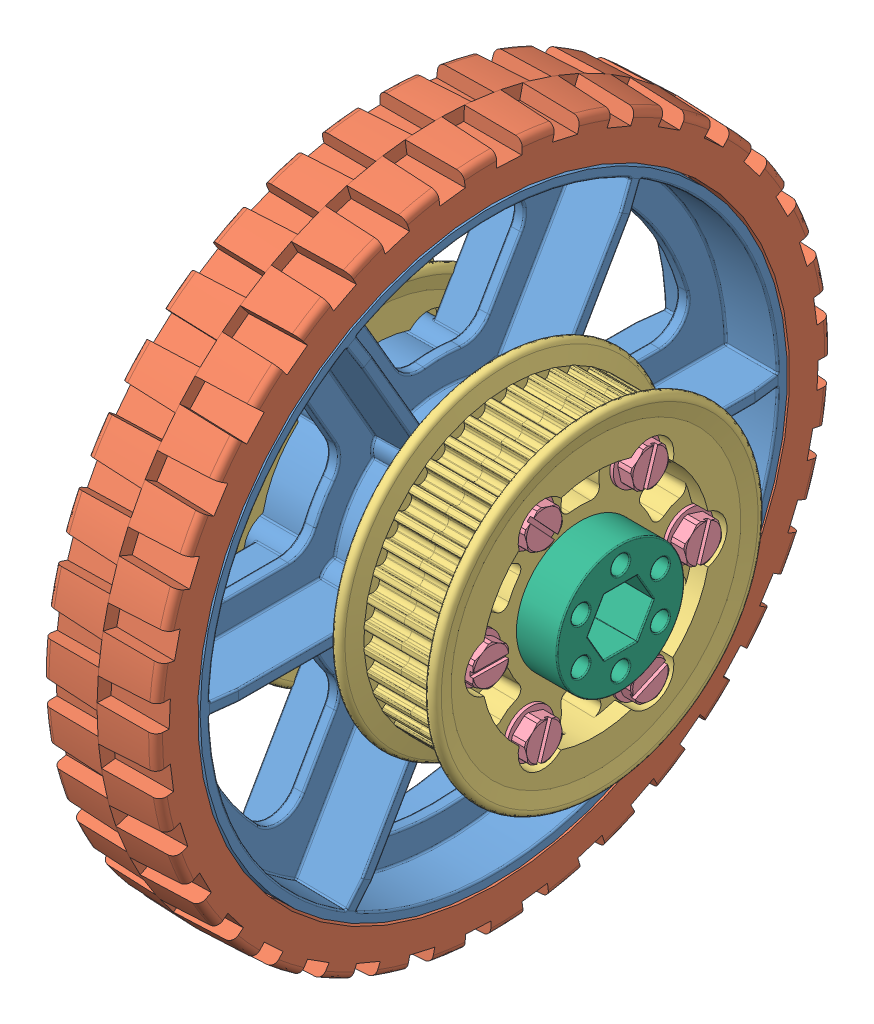
SolidWorks assembly Wheel_6inHiGrip_Center, configuration Default. Lengths in mm.
Overall size (81.42 191.55 191.55).
21 component instances, 6 part files, 0 mates.
Components (placement in the parent):
- Wheel_6inHiGrip-1: Wheel_6inHiGrip [Default] at (83.7987 67.439 110.9939) size (34.93 191.55 191.55)
  - Wheel_6inHiGrip_Wheel-1: Wheel_6inHiGrip_Wheel [Default] at (-52.6446 9.4231 21.378) size (34.93 132.08 132.08)
  - Wheel_6inHiGrip_Tread-1: Wheel_6inHiGrip_Tread [Default] at (-65.3446 9.4231 21.378) x (0 -0.304368 -0.952555) z (1 0 0) size (152.4 152.4 25.58)
- HalfPulley_42t5mm-1: HalfPulley_42t5mm [Default] at (47.6006 76.862 132.3719) x (1 0 0) z (0 -0.5 0.866025) size (13 74.23 74.23)
- HalfPulley_42t5mm-2: HalfPulley_42t5mm [Default] at (64.263 76.862 132.3719) x (-1 0 0) z (0 -0.499927 0.866067) size (13 74.23 74.23)
- ThreadFormingScrew_10-24x1.25_93882A213-1: ThreadFormingScrew_10-24x1.25_93882A213 [Default] at (63.247 76.8605 108.5602) x (0 0.953802 -0.300437) z (1 0 0) size (10.52 10.52 35.59)
- ThreadFormingScrew_10-24x1.25_93882A213-2: ThreadFormingScrew_10-24x1.25_93882A213 [Default] at (63.247 97.4833 120.4656) x (0 0.953802 -0.300437) z (1 0 0) size (10.52 10.52 35.59)
- ThreadFormingScrew_10-24x1.25_93882A213-3: ThreadFormingScrew_10-24x1.25_93882A213 [Default] at (63.247 56.2398 144.2799) x (0 0.953802 -0.300437) z (1 0 0) size (10.52 10.52 35.59)
- ThreadFormingScrew_10-24x1.25_93882A213-4: ThreadFormingScrew_10-24x1.25_93882A213 [Default] at (63.247 76.8625 156.1852) x (0 -0.013882 -0.999904) z (1 0 0) size (10.52 10.52 35.59)
- ThreadFormingScrew_10-24x1.25_93882A213-5: ThreadFormingScrew_10-24x1.25_93882A213 [Default] at (63.247 97.4843 144.2781) x (0 -0.733065 -0.680158) z (1 0 0) size (10.52 10.52 35.59)
- ThreadFormingScrew_10-24x1.25_93882A213-6: ThreadFormingScrew_10-24x1.25_93882A213 [Default] at (63.247 56.2388 120.4674) x (0 0.407306 -0.913292) z (1 0 0) size (10.52 10.52 35.59)
- HalfPulley_42t5mm-3: HalfPulley_42t5mm [Default] at (-1.9548 76.862 132.3719) x (1 0 0) z (0 -1 -0.000063) size (13 74.23 74.23)
- HalfPulley_42t5mm-4: HalfPulley_42t5mm [Default] at (14.7076 76.862 132.3719) x (-1 0 0) z (0 -1 0.000021) size (13 74.23 74.23)
- HexHub_500EX-1: HexHub_500EX [Default] at (-8.3048 76.862 132.3719) x (0 -0.866025 -0.5) z (0 -0.5 0.866025) size (55.37 25.4 51.33)
- ThreadFormingScrew_10-24x1.25_93882A213-7: ThreadFormingScrew_10-24x1.25_93882A213 [Default] at (-5.2568 97.4843 120.4656) x (0 -0.953802 0.300437) z (-1 0 0) size (10.52 10.52 35.59)
- ThreadFormingScrew_10-24x1.25_93882A213-8: ThreadFormingScrew_10-24x1.25_93882A213 [Default] at (-5.2568 76.862 108.5594) x (0 -0.953802 0.300437) z (-1 0 0) size (10.52 10.52 35.59)
- ThreadFormingScrew_10-24x1.25_93882A213-9: ThreadFormingScrew_10-24x1.25_93882A213 [Default] at (-5.2568 56.2398 120.4656) x (0 -0.953802 0.300437) z (-1 0 0) size (10.52 10.52 35.59)
- ThreadFormingScrew_10-24x1.25_93882A213-10: ThreadFormingScrew_10-24x1.25_93882A213 [Default] at (-5.2568 97.4843 144.2781) x (0 -0.192002 -0.981394) z (-1 0 0) size (10.52 10.52 35.59)
- ThreadFormingScrew_10-24x1.25_93882A213-11: ThreadFormingScrew_10-24x1.25_93882A213 [Default] at (-5.2568 56.2398 144.2781) x (0 -0.986288 0.16503) z (-1 0 0) size (10.52 10.52 35.59)
- ThreadFormingScrew_10-24x1.25_93882A213-12: ThreadFormingScrew_10-24x1.25_93882A213 [Default] at (-5.2568 76.862 156.1844) x (0 -0.150217 -0.988653) z (-1 0 0) size (10.52 10.52 35.59)
- Spacer_Hex_0.57x0.5-1: Spacer_Hex_0.57x0.5 [Default] at (57.8495 76.862 132.3719) x (0 -0.866025 -0.5) z (0 -0.5 0.866025) size (28.55 14.48 28.55)
